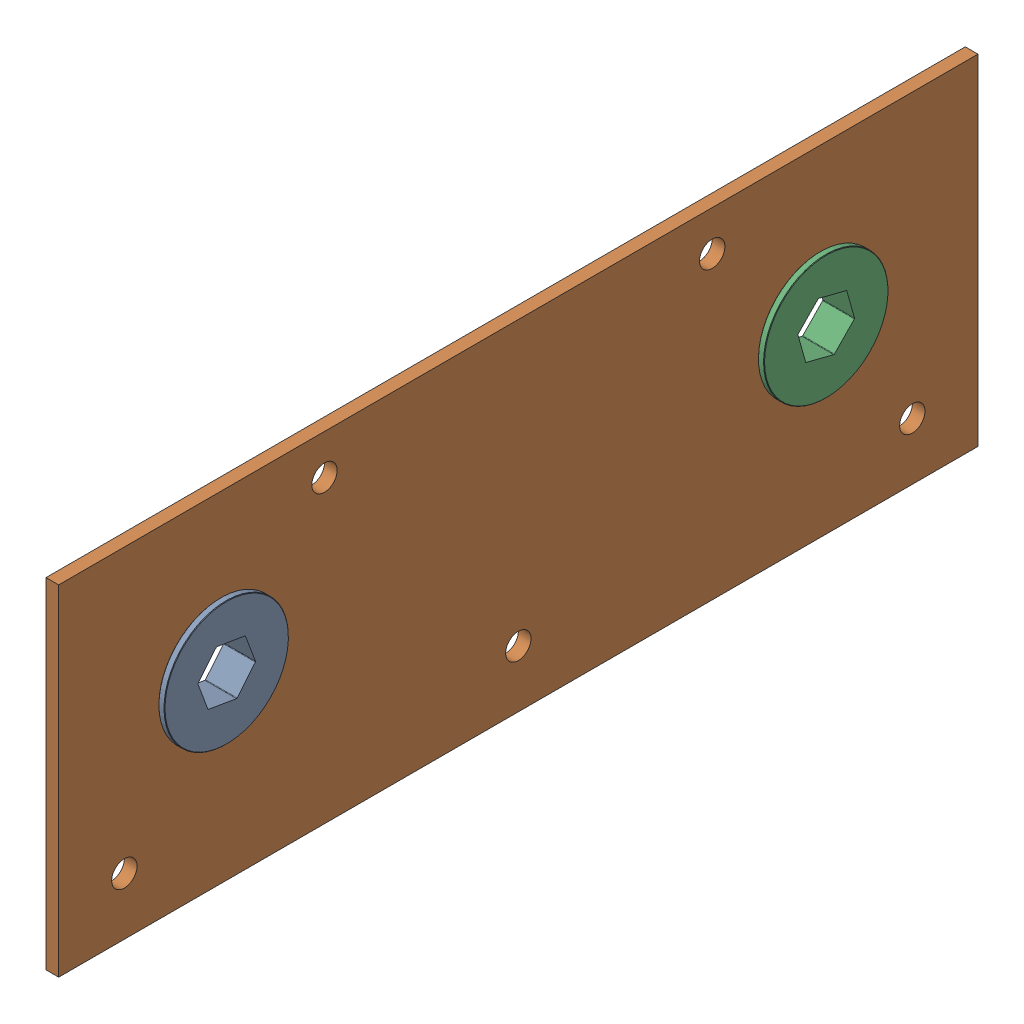
SolidWorks assembly Intake_Top_Bearing_Plate_Assembly_1, configuration Default. Lengths in mm.
Overall size (7.93 85 230).
3 component instances, 2 part files, 0 mates.
Components (placement in the parent):
- 1_2_Hex_Bore_Flange_Bearing-1: 1_2_Hex_Bore_Flange_Bearing [Default] at (-65.8953 -24.7712 75) x (0 0.16623 0.986087) z (1 0 0) size (31.12 31.12 7.93)
- Intake_Top_Bottom_Bearing_Plate-1: Intake_Top_Bottom_Bearing_Plate [Default] at (-63.175 -29.2712 0) size (3.17 85 230)
- 1_2_Hex_Bore_Flange_Bearing-2: 1_2_Hex_Bore_Flange_Bearing [Default] at (-65.8953 -24.7712 -75) x (0 -0.715549 0.698562) z (1 0 0) size (31.12 31.12 7.93)
